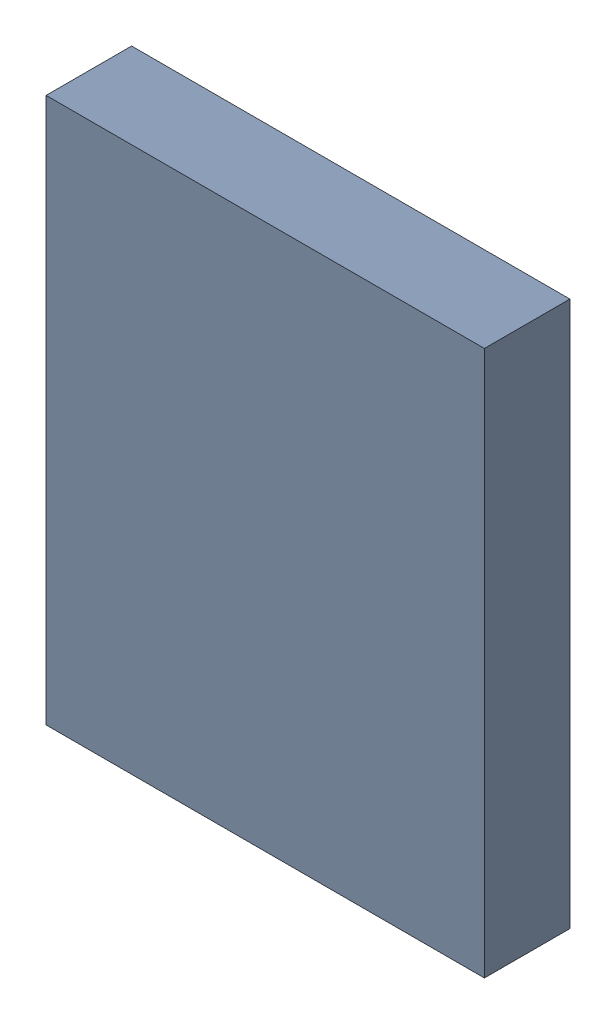
SolidWorks assembly U3, configuration ﾃﾞﾌｫﾙﾄ. Lengths in mm.
Overall size (4.1 5.1 0.8).
2 component instances, 1 part files, 0 mates.
Components (placement in the parent):
- 689262056-1: 689262056 [ﾃﾞﾌｫﾙﾄ] at (66 58 0) size (4.1 5.1 0.8)
  - Extruded_37-1: Extruded_37 [ﾃﾞﾌｫﾙﾄ] at origin size (4.1 5.1 0.8)
